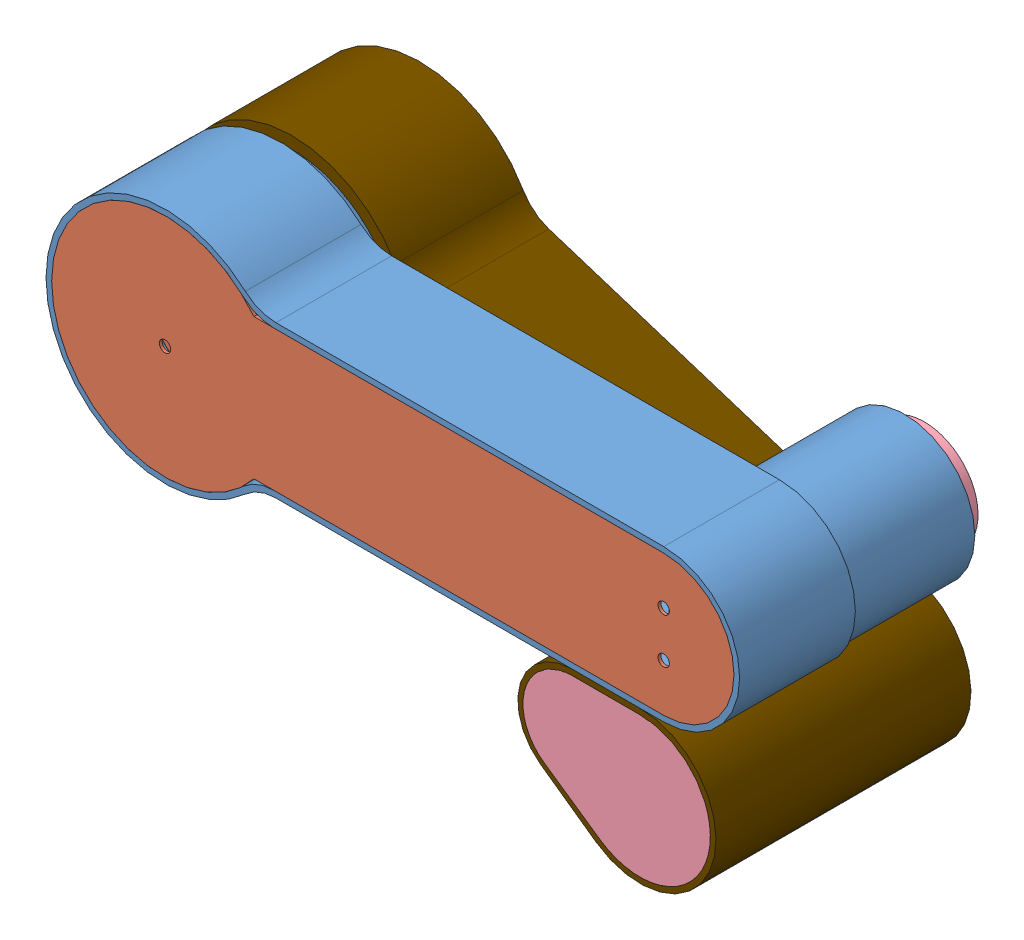
SolidWorks assembly Gibbot, configuration Default. Lengths in mm.
Overall size (410.77 245.37 146.05).
81 component instances, 22 part files, 12 mates.
Components (placement in the parent):
- Motor Link Assembly-1: Motor Link Assembly [Default] at (-110.8065 11.9629 55.9406) size (388.62 133.35 146.05)
  - Motor Link Frame-1: Motor Link Frame [Default] at (-32.059 -6.6158 -42.0522) size (388.62 133.35 134.94)
  - EC60 Motor-1: EC60 Motor [Default] at (-32.059 -6.6158 -36.2772) x (0 0 1) z (-0.866025 0.5 0) size (61.3 68 68)
  - Bearing - .750-1: Bearing - .750 [3760T241] at (247.341 -6.6158 -72.6122) x (-0.051747 0.99866 0) z (0 0 -1) size (41.27 41.27 11.11)
  - Bearing - .750-2: Bearing - .750 [3760T241] at (247.341 -6.6158 -61.4997) x (0.885753 0.464157 0) z (0 0 -1) size (41.27 41.27 11.11)
  - EM237 Magnet-1: EM237 Magnet [Default] at (247.341 -6.6158 -110.7589) x (0.987894 0.15513 0) z (-0.15513 0.987894 0) size (60.08 25.02 60.08)
  - Magnet Holder Motor Link-1: Magnet Holder Motor Link [Default] at (249.9239 -3.5616 -98.2494) x (0.645723 0.763572 0) z (0.763572 -0.645723 0) size (50.8 73.42 50.6)
  - Shaft_Carrier_Combined-1: Shaft_Carrier_Combined [Default] at (-32.059 -6.6158 -64.5147) x (0 -1 0) z (1 0 0) size (91.44 67.85 91.44)
  - Magnet Encoders E3-X-750-X-H-D-X-1: Magnet Encoders E3-X-750-X-H-D-X [Default] at (247.341 -6.6158 -32.2732) x (-0.000397 -1 0) z (-1 0.000397 0) size (55.98 16.26 66.52)
  - PCB_Battery Assembly-1: PCB_Battery Assembly [Default] at (208.1442 -28.2471 85.1479) x (1 0 0) z (0 1 0) size (127.38 21.9 77.22)
    - Battery PCB-1: Battery PCB [Default] at (-148.3186 115.135 -16.9005) x (1 0 0) z (0 -1 0) size (127.38 77.06 1.59)
    - Battery Assembly-1: Battery Assembly [Default] at (-101.6605 145.5711 -35.2548) x (-1 0 0) z (0 0 1) size (20.65 21.9 77.14)
      - Battery Holder - keystone-PN1043-1: Battery Holder - keystone-PN1043 [Default] at (27.979 42.1729 59.6018) size (20.65 18.93 77.14)
      - battery_6612-1: battery_6612 [Default] at (36.333 41.1675 88.8909) x (1 0 0) z (0 1 0) size (18.3 65.05 18.3)
    - Battery Assembly-2: Battery Assembly [Default] at (-130.4862 145.5711 78.5174) x (1 0 0) z (0 0 -1) size (20.65 21.9 77.14)
      - Battery Holder - keystone-PN1043-1: Battery Holder - keystone-PN1043 [Default] at (27.979 42.1729 59.6018) size (20.65 18.93 77.14)
      - battery_6612-1: battery_6612 [Default] at (36.333 41.1675 88.8909) x (1 0 0) z (0 1 0) size (18.3 65.05 18.3)
    - Battery Assembly-3: Battery Assembly [Default] at (-13.9797 145.5711 -35.2548) x (-1 0 0) z (0 0 1) size (20.65 21.9 77.14)
      - Battery Holder - keystone-PN1043-1: Battery Holder - keystone-PN1043 [Default] at (27.979 42.1729 59.6018) size (20.65 18.93 77.14)
      - battery_6612-1: battery_6612 [Default] at (36.333 41.1675 88.8909) x (1 0 0) z (0 1 0) size (18.3 65.05 18.3)
    - Battery Assembly-4: Battery Assembly [Default] at (-108.566 145.5711 78.5174) x (1 0 0) z (0 0 -1) size (20.65 21.9 77.14)
      - Battery Holder - keystone-PN1043-1: Battery Holder - keystone-PN1043 [Default] at (27.979 42.1729 59.6018) size (20.65 18.93 77.14)
      - battery_6612-1: battery_6612 [Default] at (36.333 41.1675 88.8909) x (1 0 0) z (0 1 0) size (18.3 65.05 18.3)
    - Battery Assembly-5: Battery Assembly [Default] at (-79.7403 145.5711 -35.2548) x (-1 0 0) z (0 0 1) size (20.65 21.9 77.14)
      - Battery Holder - keystone-PN1043-1: Battery Holder - keystone-PN1043 [Default] at (27.979 42.1729 59.6018) size (20.65 18.93 77.14)
      - battery_6612-1: battery_6612 [Default] at (36.333 41.1675 88.8909) x (1 0 0) z (0 1 0) size (18.3 65.05 18.3)
  - 10-32 Button Cap Screw-1: 10-32 Button Cap Screw [92949A271] at (6.041 6.0842 -33.1368) x (-0.172399 -0.985027 0) z (0 0 1) size (9.17 9.17 28.15)
  - 10-32 Thread Locking Nut-1: 10-32 Thread Locking Nut [90631A411] at (6.041 -19.3158 -48.4022) x (1 0 0) z (0 1 0) size (9.53 6.11 11)
  - 10-32 Button Cap Screw-2: 10-32 Button Cap Screw [92949A271] at (-70.159 6.0842 -33.1368) x (-0.097934 0.995193 0) z (0 0 1) size (9.17 9.17 28.15)
  - 10-32 Button Cap Screw-3: 10-32 Button Cap Screw [92949A271] at (-70.159 -19.3158 -33.1368) x (0.822451 -0.568836 0) z (0 0 1) size (9.17 9.17 28.15)
  - 10-32 Button Cap Screw-4: 10-32 Button Cap Screw [92949A271] at (6.041 -19.3158 -33.1368) x (0.999756 0.022081 0) z (0 0 1) size (9.17 9.17 28.15)
  - 10-32 Thread Locking Nut-2: 10-32 Thread Locking Nut [90631A411] at (6.041 6.0842 -48.4022) x (1 0 0) z (0 1 0) size (9.53 6.11 11)
  - 10-32 Thread Locking Nut-3: 10-32 Thread Locking Nut [90631A411] at (-70.159 6.0842 -48.4022) x (1 0 0) z (0 1 0) size (9.53 6.11 11)
  - 10-32 Thread Locking Nut-4: 10-32 Thread Locking Nut [90631A411] at (-70.159 -19.3158 -48.4022) x (1 0 0) z (0 1 0) size (9.53 6.11 11)
  - 5-40 Bolt-1: 5-40 Bolt [91251A131] at (53.4755 -38.7976 -47.4497) x (-0.923728 -0.383049 0) z (0 0 -1) size (5.21 5.21 22.65)
  - 5-40 Bolt-2: 5-40 Bolt [91251A131] at (53.4755 25.566 -47.4497) x (-0.923728 -0.383049 0) z (0 0 -1) size (5.21 5.21 22.65)
  - 5-40 Bolt-3: 5-40 Bolt [91251A131] at (174.5065 -38.7976 -47.4497) x (-0.923728 -0.383049 0) z (0 0 -1) size (5.21 5.21 22.65)
  - 5-40 Bolt-4: 5-40 Bolt [91251A131] at (174.5065 25.566 -47.4497) x (-0.923728 -0.383049 0) z (0 0 -1) size (5.21 5.21 22.65)
  - 5-40 Nylon Locknut-1: 5-40 Nylon Locknut [90633A006] at (53.4755 -38.7976 -42.0522) x (1 0 0) z (0 1 0) size (6.35 2.87 7.33)
  - 5-40 Nylon Locknut-2: 5-40 Nylon Locknut [90633A006] at (174.5065 -38.7976 -42.0522) x (1 0 0) z (0 1 0) size (6.35 2.87 7.33)
  - 5-40 Nylon Locknut-3: 5-40 Nylon Locknut [90633A006] at (53.4755 25.566 -42.0522) x (1 0 0) z (0 1 0) size (6.35 2.87 7.33)
  - 5-40 Nylon Locknut-4: 5-40 Nylon Locknut [90633A006] at (174.5065 25.566 -42.0522) x (1 0 0) z (0 1 0) size (6.35 2.87 7.33)
  - M5 Nylon Spacer-1: M5 Nylon Spacer [93657A042] at (256.097 8.5361 -17.0812) x (0.923728 0.383049 0) z (0 0 -1) size (8 8 6)
  - M5 Nylon Spacer-2: M5 Nylon Spacer [93657A042] at (229.841 -6.6089 -17.0812) x (0.923728 0.383049 0) z (0 0 -1) size (8 8 6)
  - M5 Nylon Spacer-3: M5 Nylon Spacer [93657A042] at (256.085 -21.7748 -17.0812) x (0.923728 0.383049 0) z (0 0 -1) size (8 8 6)
  - Slip Ring M322M1-0202-1: Slip Ring M322M1-0202 [Default] at (247.341 -6.6158 -11.6812) x (-0.866224 -0.499656 0) z (0 0 -1) size (44 44 57)
- Wall Link Assembly-1: Wall Link Assembly [Default] at (195.1563 -82.1651 -38.4397) x (0.952498 -0.304545 0) z (-0.304545 -0.952498 0) size (388.62 146.05 133.35)
  - magnet holder-1: magnet holder [Default] at (-69.5408 -3.8692 23.5746) x (-0.081084 0 0.996707) z (-0.996707 0 -0.081084) size (50.8 63.9 50.6)
  - Wall Link Frame-1: Wall Link Frame [Default] at (-348.6164 39.6281 19.5878) x (1 0 0) z (0 -1 0) size (388.62 133.35 142.88)
  - Bearing - .750-1: Bearing - .750 [3760T241] at (-69.2164 21.7681 19.5878) x (0.982823 0 0.184551) z (0 -1 0) size (41.27 41.27 11.11)
  - Bearing - .750-2: Bearing - .750 [3760T241] at (-69.2164 32.8806 19.5878) x (0.837169 0 0.546944) z (0 1 0) size (41.27 41.27 11.11)
  - Bearing - .750-3: Bearing - .750 [3760T241] at (-348.6164 6.5421 19.5878) x (0.79819 0 0.602406) z (0 1 0) size (41.27 41.27 11.11)
  - Bearing - .750-4: Bearing - .750 [3760T241] at (-348.6164 17.6546 19.5878) x (0.713431 0 0.700725) z (0 1 0) size (41.27 41.27 11.11)
  - Magnet Encoders E3-X-750-X-H-D-X-1: Magnet Encoders E3-X-750-X-H-D-X [Default] at (-69.2164 52.5821 19.5878) x (0 0 1) z (-1 0 0) size (55.98 16.26 66.52)
  - EM237 Magnet-1: EM237 Magnet [Default] at (-69.2164 -16.3787 19.5878) x (0.767455 0 -0.641103) z (-0.641103 0 -0.767455) size (60.08 25.02 60.08)
  - Ring Gear-1: Ring Gear [Default] at (-348.6168 41.9781 19.5878) x (0 -1 0) z (0 0 1) size (8 120 120)
  - Magnet Encoders E3-X-750-X-H-D-X-2: Magnet Encoders E3-X-750-X-H-D-X [Default] at (-348.6164 -5.6182 19.5878) x (0 0 1) z (1 0 0) size (55.98 16.26 66.52)
  - Slip Ring M322M1-0202-1: Slip Ring M322M1-0202 [Default] at (-69.2164 73.1741 19.5878) x (0.866025 0 0.5) z (0 -1 0) size (44 44 57)
  - M5 Nylon Spacer-1: M5 Nylon Spacer [93657A042] at (-60.4664 67.7741 34.7433) x (0.837169 0 0.546944) z (0 -1 0) size (8 8 6)
  - M5 Nylon Spacer-2: M5 Nylon Spacer [93657A042] at (-60.4664 67.7741 4.4324) x (0.552857 0 0.833276) z (0 -1 0) size (8 8 6)
  - M5 Nylon Spacer-3: M5 Nylon Spacer [93657A042] at (-86.7164 67.7741 19.5878) x (0.837169 0 0.546944) z (0 -1 0) size (8 8 6)
  - PCB_Battery Assembly-1: PCB_Battery Assembly [Default] at (-108.4133 -78.6819 -2.0435) size (127.38 21.9 77.22)
    - Battery PCB-1: Battery PCB [Default] at (-148.3186 115.135 -16.9005) x (1 0 0) z (0 -1 0) size (127.38 77.06 1.59)
    - Battery Assembly-1: Battery Assembly [Default] at (-101.6605 145.5711 -35.2548) x (-1 0 0) z (0 0 1) size (20.65 21.9 77.14)
      - Battery Holder - keystone-PN1043-1: Battery Holder - keystone-PN1043 [Default] at (27.979 42.1729 59.6018) size (20.65 18.93 77.14)
      - battery_6612-1: battery_6612 [Default] at (36.333 41.1675 88.8909) x (1 0 0) z (0 1 0) size (18.3 65.05 18.3)
    - Battery Assembly-2: Battery Assembly [Default] at (-130.4862 145.5711 78.5174) x (1 0 0) z (0 0 -1) size (20.65 21.9 77.14)
      - Battery Holder - keystone-PN1043-1: Battery Holder - keystone-PN1043 [Default] at (27.979 42.1729 59.6018) size (20.65 18.93 77.14)
      - battery_6612-1: battery_6612 [Default] at (36.333 41.1675 88.8909) x (1 0 0) z (0 1 0) size (18.3 65.05 18.3)
    - Battery Assembly-3: Battery Assembly [Default] at (-13.9797 145.5711 -35.2548) x (-1 0 0) z (0 0 1) size (20.65 21.9 77.14)
      - Battery Holder - keystone-PN1043-1: Battery Holder - keystone-PN1043 [Default] at (27.979 42.1729 59.6018) size (20.65 18.93 77.14)
      - battery_6612-1: battery_6612 [Default] at (36.333 41.1675 88.8909) x (1 0 0) z (0 1 0) size (18.3 65.05 18.3)
    - Battery Assembly-4: Battery Assembly [Default] at (-108.566 145.5711 78.5174) x (1 0 0) z (0 0 -1) size (20.65 21.9 77.14)
      - Battery Holder - keystone-PN1043-1: Battery Holder - keystone-PN1043 [Default] at (27.979 42.1729 59.6018) size (20.65 18.93 77.14)
      - battery_6612-1: battery_6612 [Default] at (36.333 41.1675 88.8909) x (1 0 0) z (0 1 0) size (18.3 65.05 18.3)
    - Battery Assembly-5: Battery Assembly [Default] at (-79.7403 145.5711 -35.2548) x (-1 0 0) z (0 0 1) size (20.65 21.9 77.14)
      - Battery Holder - keystone-PN1043-1: Battery Holder - keystone-PN1043 [Default] at (27.979 42.1729 59.6018) size (20.65 18.93 77.14)
      - battery_6612-1: battery_6612 [Default] at (36.333 41.1675 88.8909) x (1 0 0) z (0 1 0) size (18.3 65.05 18.3)
- Motor Link Cover-1: Motor Link Cover [Default] at (-142.8655 5.3471 77.1344) size (382.27 127 1.59)
- Wall Link Cover-1: Wall Link Cover [Default] at (-142.8655 5.3471 -64.1531) x (0.952498 -0.304545 0) z (0 0 1) size (317 127 1.59)
- Wall Link Cover 2-1: Wall Link Cover 2 [Default] at (123.2624 -79.7429 78.7219) x (0.954677 -0.297644 0) z (0 0 -1) size (106.77 78.74 1.59)
Mates (geometry in assembly coordinates):
- Concentric1: concentric aligned: cylinder of Motor Link Assembly-1/Shaft_Carrier_Combined-1 through (-142.8655 5.3471 -53.9639) axis (0 0 1) radius 9.525; cylinder of Wall Link Assembly-1/Bearing - .750-3 through (-142.8655 5.3471 -26.3414) axis (0 0 1) radius 9.525
- Coincident8: coincident anti-aligned: plane of Motor Link Assembly-1/Motor Link Frame-1 through (136.5345 -37.1979 78.7219) normal (0 -1 0); plane of Wall Link Assembly-1/Wall Link Frame-1 through (123.2624 -37.1979 220.1029) normal (0 1 0)
- Coincident9: coincident anti-aligned: plane of Motor Link Assembly-1/Shaft_Carrier_Combined-1 through (-142.8655 5.3471 -15.2289) normal (0 0 -1); plane of Wall Link Assembly-1/Bearing - .750-4 through (-130.6959 11.759 -15.2289) normal (0 0 1)
- Coincident10: coincident anti-aligned: plane of Wall Link Assembly-1/Wall Link Frame-1 through (-142.8655 5.3471 -62.5656) normal (0 0 -1); plane of Wall Link Cover-1 through (82.001 -102.8837 -62.5656) normal (0 0 1)
- Concentric2: concentric anti-aligned: cylinder of Motor Link Assembly-1/Shaft_Carrier_Combined-1 through (-142.8655 5.3471 -15.2289) axis (0 0 1) radius 6.35; cylinder of Wall Link Cover-1 through (-142.8655 5.3471 -62.5656) axis (0 0 -1) radius 3.175
- Parallel1: parallel anti-aligned: plane of Wall Link Assembly-1/Wall Link Frame-1 through (-107.3999 -47.3259 -64.1531) normal (0.304545 0.952498 0); plane of Wall Link Cover-1 through (80.0671 -108.9321 -62.5656) normal (-0.304545 -0.952498 0)
- Coincident12: coincident anti-aligned: plane of Motor Link Assembly-1/Motor Link Frame-1 through (-142.8655 5.3471 77.1344) normal (0 0 1); plane of Motor Link Cover-1 through (136.5345 5.3471 77.1344) normal (0 0 -1)
- Concentric3: concentric anti-aligned: cylinder of Motor Link Assembly-1/EC60 Motor-1 through (-142.8655 5.3471 -3.4366) axis (0 0 1) radius 30; cylinder of Motor Link Cover-1 through (-142.8655 5.3471 78.7219) axis (0 0 -1) radius 3.175
- Coincident13: coincident anti-aligned: plane of Motor Link Assembly-1/Motor Link Frame-1 through (136.5345 44.7171 78.7219) normal (0 -1 0); plane of Motor Link Cover-1 through (136.5345 44.7171 78.7219) normal (0 1 0)
- Coincident14: coincident anti-aligned: plane of Wall Link Assembly-1/Wall Link Frame-1 through (-142.8655 5.3471 77.1344) normal (0 0 1); plane of Wall Link Cover 2-1 through (123.2624 -79.7429 77.1344) normal (0 0 -1)
- Concentric4: concentric anti-aligned: cylinder of Wall Link Assembly-1/Wall Link Frame-1 through (123.2624 -79.7429 220.1029) axis (0 0 -1) radius 39.37; cylinder of Wall Link Cover 2-1 through (123.2624 -79.7429 77.1344) axis (0 0 1) radius 39.37
- Coincident15: coincident anti-aligned: plane of Wall Link Assembly-1/Wall Link Frame-1 through (123.2624 -40.3729 220.1029) normal (0 -1 0); plane of Wall Link Cover 2-1 through (123.2624 -40.3729 77.1344) normal (0 1 0)
